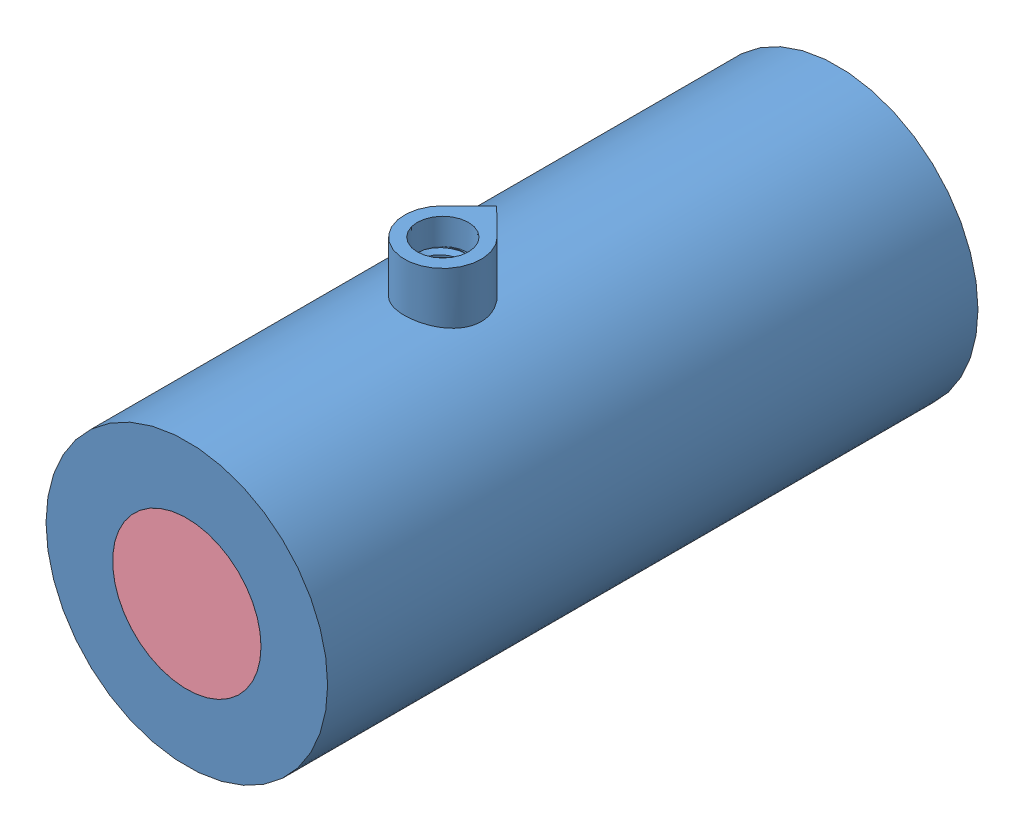
SolidWorks assembly globe_valve_005-2, configuration Default. Lengths in mm.
Overall size (22 25.8 50.81).
5 component instances, 5 part files, 4 mates.
Components (placement in the parent):
- globe_valve_test-005-1: globe_valve_test-005 [Default] at (24.4644 27.9344 35.1224) size (22 25.8 50.8)
- LID4-1: LID4 [Default] at origin size (4 0.31 4)
- LID5-1: LID5 [Default] at origin size (11.86 11.86 0.32)
- LID6-1: LID6 [Default] at origin size (11.86 11.86 0.32)
- globe_valve_test-005_stopper-002-1: globe_valve_test-005_stopper-002 [Default] at (24.4644 35.3344 65.9224) x (0.131907 0 -0.991262) z (0.991262 0 0.131907) size (8.2 7.04 8.2)
Mates (geometry in assembly coordinates):
- Concentric1: concentric: cylinder of globe_valve_test-005-1 through (24.4644 27.9334 65.9224) axis (0 1 0) radius 2; cylinder of globe_valve_test-005_stopper-002-1 through (24.4644 38.9344 65.9224) axis (0 1 0) radius 2
- Concentric2: concentric: cylinder of globe_valve_test-005-1 through (24.4644 36.7344 65.9224) axis (0 -1 0) radius 2.1; cylinder of globe_valve_test-005_stopper-002-1 through (24.4644 35.3344 65.9224) axis (0 -1 0) radius 2.1
- Width1: width = 1.4 mm: plane of globe_valve_test-005-1 through (66.7709 37.9344 71.7224) normal (0 1 0); plane of globe_valve_test-005-1 through (24.4644 42.3344 65.9224) normal (0 -1 0); plane of globe_valve_test-005_stopper-002-1 through (21.3915 39.3344 65.5135) normal (0 -1 0); plane of globe_valve_test-005_stopper-002-1 through (20.4002 40.7344 65.3816) normal (0 1 0)
- Tangent1: tangent: cylinder of globe_valve_test-005-1 through (24.4644 38.9344 35.1224) axis (0 0 1) radius 5; sphere of globe_valve_test-005_stopper-002-1
